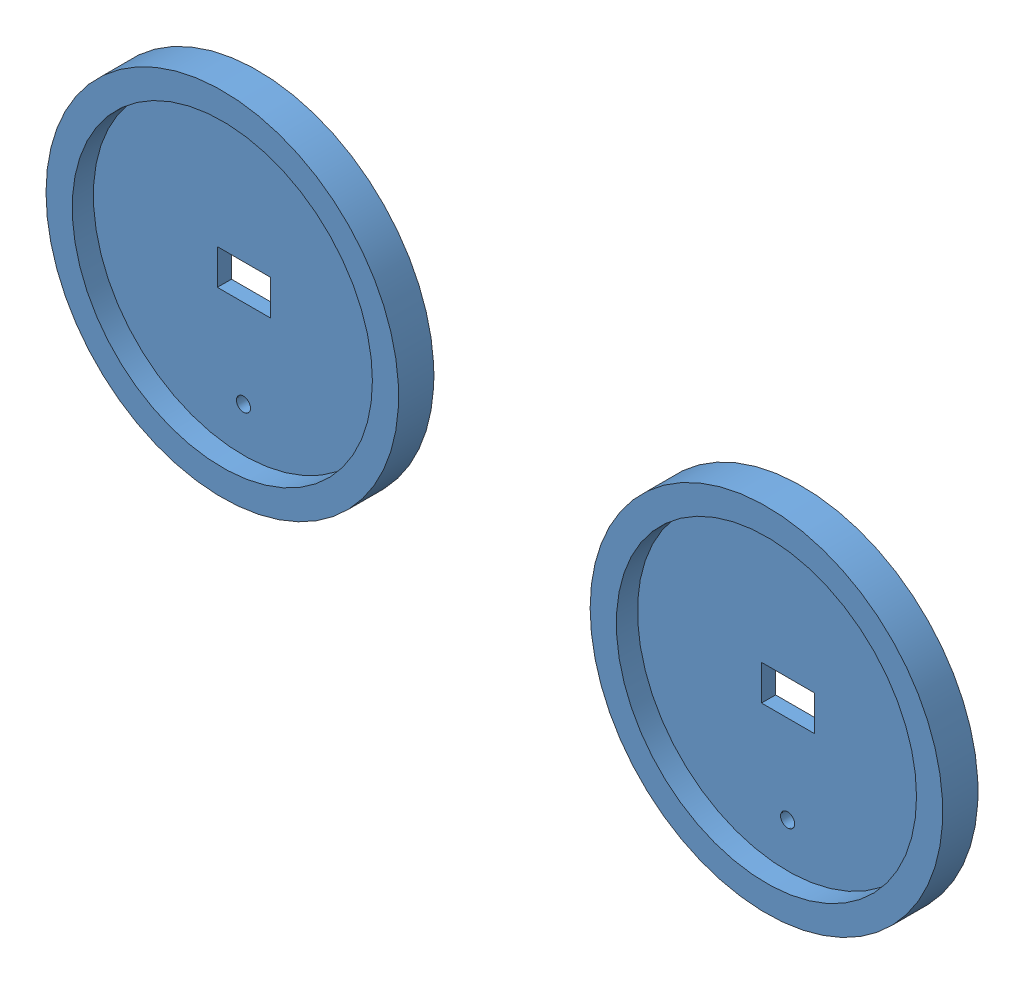
SolidWorks assembly Assemblage1, configuration Défaut. Lengths in mm.
Overall size (127.16 62.47 5).
2 component instances, 1 part files, 1 mates.
Components (placement in the parent):
- Roue-1: Roue [Défaut] at (-14.2908 -0.4435 -2.5) size (50 50 5)
- Roue-2: Roue [Défaut] at (-91.4477 12.0272 -2.5) size (50 50 5)
Mates (geometry in assembly coordinates):
- Coïncidente1: coincident aligned: plane of Roue-1 through (-14.2908 -0.4435 -2.5) normal (0 0 -1); plane of Roue-2 through (-91.4477 12.0272 -2.5) normal (0 0 -1)
